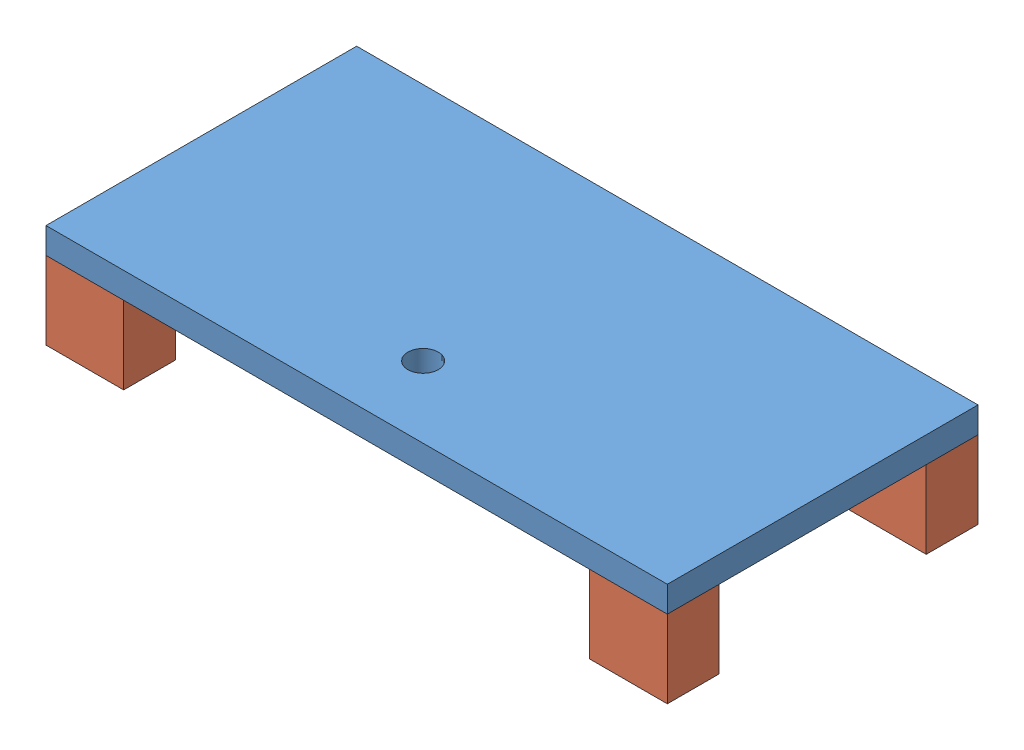
SolidWorks assembly BaseAssembly, configuration Default. Lengths in mm.
Overall size (609.6 153 408.02).
18 component instances, 8 part files, 37 mates.
Components (placement in the parent):
- Baseplate-2: Baseplate [Default] at (-220.0333 49.3507 119.3051) size (609.6 25.4 304.8)
- BaseFlat-1: BaseFlat [Default] at (-220.0333 100.7507 114.3051) size (600 25.4 127) (hidden)
- ShortSpacer-1: ShortSpacer [Default] at (-180.0333 74.7507 89.3051) size (76.2 26 50.8) (hidden)
- ShortSpacer-2: ShortSpacer [Default] at (339.9667 74.7507 9.3051) size (76.2 26 50.8) (hidden)
- ShortSpacer-3: ShortSpacer [Default] at (339.9667 74.7507 89.3051) size (76.2 26 50.8) (hidden)
- ShortSpacer-4: ShortSpacer [Default] at (-180.0333 74.7507 9.3051) size (76.2 26 50.8) (hidden)
- LongSpacer-1: LongSpacer [Default] at (-220.0333 -26.8493 119.3051) size (76.2 76.2 50.8)
- LongSpacer-2: LongSpacer [Default] at (-220.0333 -26.8493 -134.6949) size (76.2 76.2 50.8)
- LongSpacer-3: LongSpacer [Default] at (313.3667 -26.8493 -134.6949) size (76.2 76.2 50.8)
- LongSpacer-4: LongSpacer [Default] at (313.3667 -26.8493 119.3051) size (76.2 76.2 50.8)
- LongScrew-5: LongScrew [Default] at (-180.0333 125.1507 89.3051) x (-0.837169 0 -0.546944) z (-0.546944 0 0.837169) size (18 47 18) (hidden)
- LongScrew-6: LongScrew [Default] at (-180.0333 125.1507 9.3051) x (-0.837169 0 -0.546944) z (-0.546944 0 0.837169) size (18 47 18) (hidden)
- LongScrew-7: LongScrew [Default] at (339.9667 125.1507 89.3051) x (-0.837169 0 -0.546944) z (-0.546944 0 0.837169) size (18 47 18) (hidden)
- LongScrew-8: LongScrew [Default] at (339.9667 125.1507 9.3051) x (-0.837169 0 -0.546944) z (-0.546944 0 0.837169) size (18 47 18) (hidden)
- IndicatorFlat-1: IndicatorFlat [Default] at (97.4667 51.5757 119.3051) x (-1 0 0) z (0 0 -1) size (25.4 3.17 101.6) (hidden)
- Magnet-1: Magnet [Default] at (84.2223 64.7507 208.687) x (-0.837169 0 -0.546944) z (-0.546944 0 0.837169) size (20 10 20) (hidden)
- Magnet-2: Magnet [Default] at (85.5228 64.7507 188.1946) x (-0.837169 0 -0.546944) z (-0.546944 0 0.837169) size (20 10 20) (hidden)
- AngleIndicator-1: AngleIndicator [Default] at (72.0667 64.7507 220.9051) size (25.4 28.18 28.18) (hidden)
Mates (geometry in assembly coordinates):
- Concentric1: concentric aligned: circle of Baseplate-2; circle of ShortSpacer-1
- Concentric3: concentric aligned: circle of Baseplate-2; circle of ShortSpacer-4
- Concentric4: concentric aligned: circle of Baseplate-2; circle of ShortSpacer-3
- Concentric5: concentric aligned: circle of Baseplate-2; circle of ShortSpacer-2
- Coincident2: coincident anti-aligned: plane of Baseplate-2 through (-220.0333 74.7507 -185.4949) normal (0 1 0); plane of ShortSpacer-3 through (339.9667 74.7507 89.3051) normal (0 -1 0)
- Coincident3: coincident anti-aligned: plane of Baseplate-2 through (-220.0333 74.7507 -185.4949) normal (0 1 0); plane of ShortSpacer-2 through (339.9667 74.7507 9.3051) normal (0 -1 0)
- Coincident4: coincident anti-aligned: plane of Baseplate-2 through (-220.0333 74.7507 -185.4949) normal (0 1 0); plane of ShortSpacer-1 through (-180.0333 74.7507 89.3051) normal (0 -1 0)
- Coincident5: coincident anti-aligned: plane of Baseplate-2 through (-220.0333 74.7507 -185.4949) normal (0 1 0); plane of ShortSpacer-4 through (-180.0333 74.7507 9.3051) normal (0 -1 0)
- Coincident22: coincident anti-aligned: plane of Baseplate-2 through (-220.0333 49.3507 -185.4949) normal (0 -1 0); plane of LongSpacer-1 through (-220.0333 49.3507 68.5051) normal (0 1 0)
- Coincident23: coincident anti-aligned: plane of Baseplate-2 through (-220.0333 49.3507 -185.4949) normal (0 -1 0); plane of LongSpacer-2 through (-220.0333 49.3507 -185.4949) normal (0 1 0)
- Coincident24: coincident anti-aligned: plane of Baseplate-2 through (-220.0333 49.3507 -185.4949) normal (0 -1 0); plane of LongSpacer-3 through (313.3667 49.3507 -185.4949) normal (0 1 0)
- Coincident25: coincident anti-aligned: plane of Baseplate-2 through (-220.0333 49.3507 -185.4949) normal (0 -1 0); plane of LongSpacer-4 through (313.3667 49.3507 68.5051) normal (0 1 0)
- Coincident26: coincident aligned: plane of Baseplate-2 through (-220.0333 74.7507 119.3051) normal (0 0 1); plane of LongSpacer-1 through (-220.0333 49.3507 119.3051) normal (0 0 1)
- Coincident27: coincident aligned: plane of Baseplate-2 through (-220.0333 74.7507 119.3051) normal (-1 0 0); plane of LongSpacer-1 through (-220.0333 49.3507 119.3051) normal (-1 0 0)
- Coincident28: coincident aligned: plane of Baseplate-2 through (-220.0333 74.7507 119.3051) normal (-1 0 0); plane of LongSpacer-2 through (-220.0333 49.3507 -134.6949) normal (-1 0 0)
- Coincident29: coincident aligned: plane of Baseplate-2 through (-220.0333 74.7507 -185.4949) normal (0 0 -1); plane of LongSpacer-2 through (-220.0333 49.3507 -185.4949) normal (0 0 -1)
- Coincident30: coincident aligned: plane of Baseplate-2 through (-220.0333 74.7507 -185.4949) normal (0 0 -1); plane of LongSpacer-3 through (313.3667 49.3507 -185.4949) normal (0 0 -1)
- Coincident31: coincident aligned: plane of Baseplate-2 through (389.5667 74.7507 119.3051) normal (1 0 0); plane of LongSpacer-3 through (389.5667 49.3507 -134.6949) normal (1 0 0)
- Coincident32: coincident aligned: plane of Baseplate-2 through (389.5667 74.7507 119.3051) normal (1 0 0); plane of LongSpacer-4 through (389.5667 49.3507 119.3051) normal (1 0 0)
- Coincident33: coincident aligned: plane of Baseplate-2 through (-220.0333 74.7507 119.3051) normal (0 0 1); plane of LongSpacer-4 through (313.3667 49.3507 119.3051) normal (0 0 1)
- Concentric6: concentric aligned: circle of BaseFlat-1; circle of ShortSpacer-3
- Concentric7: concentric aligned: circle of BaseFlat-1; circle of ShortSpacer-4
- Coincident34: coincident anti-aligned: plane of BaseFlat-1 through (-220.0333 100.7507 -12.6949) normal (0 -1 0); plane of ShortSpacer-1 through (-141.9333 100.7507 114.7051) normal (0 1 0)
- Coincident35: coincident: circle of BaseFlat-1; circle of LongScrew-5
- Coincident36: coincident: circle of BaseFlat-1; circle of LongScrew-6
- Coincident37: coincident: circle of BaseFlat-1; circle of LongScrew-8
- Coincident38: coincident: circle of BaseFlat-1; circle of LongScrew-7
- Coincident39: coincident anti-aligned: plane of Baseplate-2 through (-220.0333 74.7507 119.3051) normal (0 0 1); plane of IndicatorFlat-1 through (97.4667 54.7507 119.3051) normal (0 0 -1)
- Parallel1: parallel aligned: plane of Baseplate-2 through (-220.0333 74.7507 -185.4949) normal (0 1 0); plane of IndicatorFlat-1 through (97.4667 54.7507 220.9051) normal (0 1 0)
- Distance2: distance = 292.1 mm aligned: plane of Baseplate-2 through (389.5667 74.7507 119.3051) normal (1 0 0); plane of IndicatorFlat-1 through (97.4667 54.7507 119.3051) normal (1 0 0)
- Distance3: distance = 20 mm aligned: plane of IndicatorFlat-1 through (97.4667 54.7507 220.9051) normal (0 1 0); plane of Baseplate-2 through (-220.0333 74.7507 -185.4949) normal (0 1 0)
- Coincident45: coincident anti-aligned: plane of IndicatorFlat-1 through (97.4667 54.7507 220.9051) normal (0 1 0); plane of Magnet-2 through (85.5228 54.7507 188.1946) normal (0 -1 0)
- Coincident46: coincident anti-aligned: plane of IndicatorFlat-1 through (97.4667 54.7507 220.9051) normal (0 1 0); plane of Magnet-1 through (84.2223 54.7507 208.687) normal (0 -1 0)
- Coincident47: coincident: plane of Magnet-1 through (84.2223 64.7507 208.687) normal (0 1 0); plane of AngleIndicator-1 through (66.332 64.7507 217.4869) normal (0 -1 0)
- Coincident48: coincident anti-aligned: plane of Magnet-2 through (85.5228 64.7507 188.1946) normal (0 1 0); plane of AngleIndicator-1 through (72.0667 64.7507 192.7301) normal (0 -1 0)
- Coincident49: coincident aligned: plane of IndicatorFlat-1 through (97.4667 54.7507 119.3051) normal (1 0 0); plane of AngleIndicator-1 through (97.4667 67.9257 220.9051) normal (1 0 0)
- Coincident50: coincident aligned: plane of IndicatorFlat-1 through (97.4667 54.7507 220.9051) normal (0 0 1); plane of AngleIndicator-1 through (72.0667 67.9257 220.9051) normal (0 0 1)
